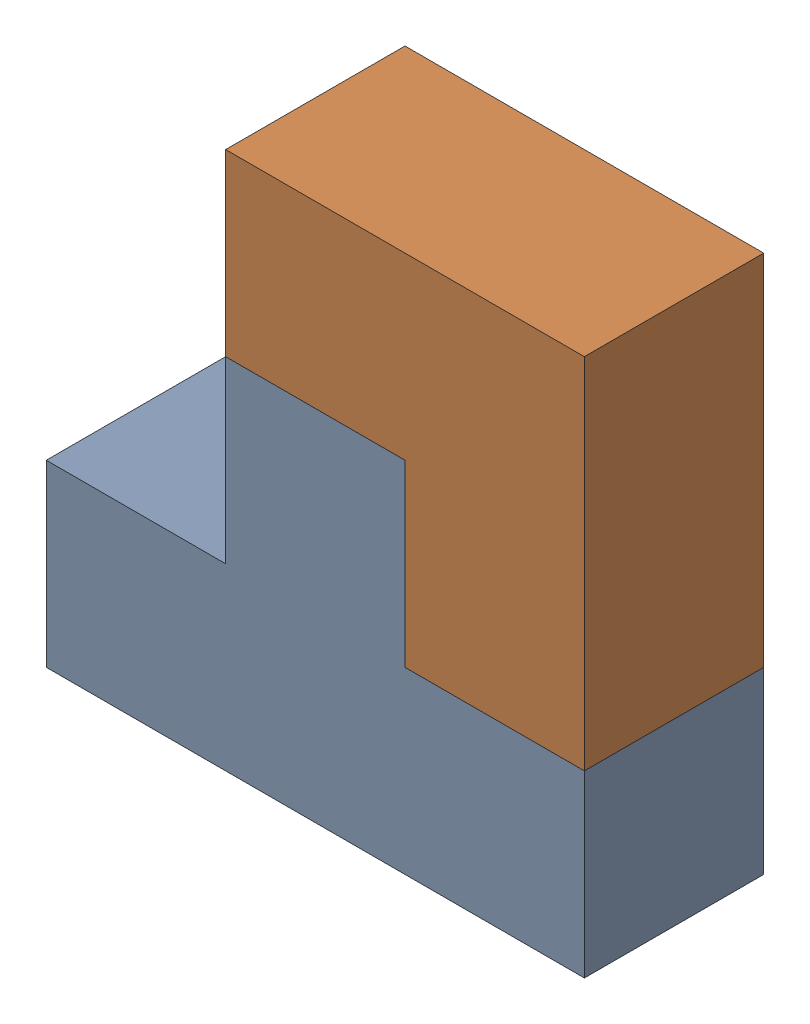
SolidWorks assembly Assem1, configuration Default. Lengths in mm.
Overall size (90 90 30).
2 component instances, 2 part files, 1 mates.
Components (placement in the parent):
- task2Part2-1: task2Part2 [Default] at (-14.9683 31.792 73.1766) size (90 60 30)
- task2Part3-1: task2Part3 [Default] at (75.0317 61.792 73.1766) x (0 1 0) z (0 0 1) size (60 60 30)
Mates (geometry in assembly coordinates):
- ProfileCenter1: profile center anti-aligned: plane of task2Part2-1 through (45.0317 91.792 103.1766) normal (0 1 0); plane of task2Part3-1 through (15.0317 91.792 103.1766) normal (0 -1 0)
